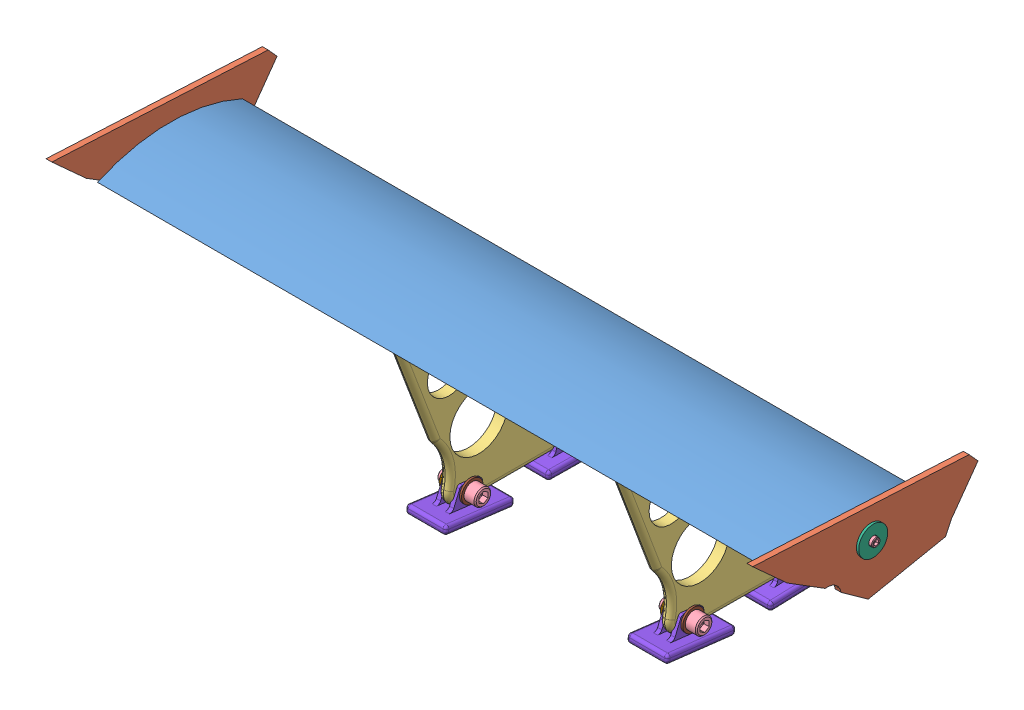
SolidWorks assembly Assem1, configuration Default. Lengths in mm.
Overall size (1241.16 472.25 542.31).
81 component instances, 11 part files, 160 mates.
Components (placement in the parent):
- Part2-1: Part2 [Default] at (342.6125 943.7855 488.4841) size (1200 61 250)
- Part3-1: Part3 [Default] at (1552.6125 952.4935 445.758) x (0 -0.051123 -0.998692) z (-1 0 0) size (390.26 137.82 10)
- Part1-1: Part1 [Default] at (760.6125 644.7182 243.5009) x (0 0.00127 0.999999) z (-1 0 0) size (353.43 346.99 18)
- Part3-2: Part3 [Default] at (342.6125 952.4935 445.758) x (0 -0.051123 -0.998692) z (-1 0 0) size (390.26 137.82 10)
- socket head cap screw_ai-2: socket head cap screw_ai [HX-SHCS 0.375-24x1.625x1.625-N] at (320.9793 952.2239 440.4907) size (50.8 14.29 14.29)
- flat washer type a selected wide_ai-1: flat washer type a selected wide_ai [Selected Wide FW 0.438] at (332.6125 952.2239 440.4907) size (2.11 34.92 34.92)
- socket head cap screw_ai-6: socket head cap screw_ai [HX-SHCS 0.375-24x0.375x0.375-N] at (1562.1375 952.2239 440.4907) x (-1 0 0) z (0 0.924225 0.381849) size (19.05 14.29 14.29)
- flat washer wide_am-1: flat washer wide_am [B18.22M - Plain washer, 14 mm, wide] at (1552.7537 952.2239 440.4907) x (-1 0 0) z (0 -0.924225 -0.381849) size (4 50 50)
- Part4-1: Part4 [Default] at (742.6125 905.2213 468.6071) x (0 0.973052 0.230586) z (-1 0 0) size (44 14 6)
- Part5-1: Part5 [Default] at (750.3125 548.0812 169.7061) x (0 -0.012088 -0.999927) z (0 0.999927 -0.012088) size (120 70 48.08)
- Part4-2: Part4 [Default] at (765.6125 909.909 397.6753) x (0 -0.859139 0.511742) z (-1 0 0) size (44 14 6)
- Part4-3: Part4 [Default] at (765.6125 907.4668 469.1392) x (0 -0.973052 -0.230586) z (-1 0 0) size (44 14 6)
- Part4-4: Part4 [Default] at (742.6125 909.909 397.6753) x (0 -0.859139 0.511742) z (-1 0 0) size (44 14 6)
- Part1-2: Part1 [Default] at (1143.6125 643.7923 244.3096) x (0 0.005793 0.999983) z (-1 0 0) size (353.43 346.99 18)
- Part4-5: Part4 [Default] at (1148.6125 909.8196 397.5231) x (0 -0.865593 0.500748) z (-1 0 0) size (44 14 6)
- Part4-6: Part4 [Default] at (1148.6125 907.5016 468.9956) x (0 -0.970536 -0.240954) z (-1 0 0) size (44 14 6)
- Part4-7: Part4 [Default] at (1125.6125 907.8221 398.6787) x (0 0.865593 -0.500748) z (-1 0 0) size (44 14 6)
- Part4-8: Part4 [Default] at (1125.6125 905.2619 468.4396) x (0 0.970536 0.240954) z (-1 0 0) size (44 14 6)
- socket head cap screw_ai-7: socket head cap screw_ai [HX-SHCS 0.375-24x1.75x1.25-N] at (1107.9793 891.8237 465.1033) size (53.98 14.29 14.29)
- socket head cap screw_ai-8: socket head cap screw_ai [HX-SHCS 0.375-24x1.75x1.25-N] at (1107.9793 920.9398 472.3319) size (53.98 14.29 14.29)
- socket head cap screw_ai-9: socket head cap screw_ai [HX-SHCS 0.375-24x1.75x1.25-N] at (1107.9793 895.837 405.6121) size (53.98 14.29 14.29)
- socket head cap screw_ai-10: socket head cap screw_ai [HX-SHCS 0.375-24x1.75x1.25-N] at (1107.9793 921.8048 390.5896) size (53.98 14.29 14.29)
- socket head cap screw_ai-11: socket head cap screw_ai [HX-SHCS 0.375-24x1.75x1.25-N] at (1107.9793 895.837 405.6121) size (53.98 14.29 14.29)
- socket head cap screw_ai-12: socket head cap screw_ai [HX-SHCS 0.375-24x1.75x1.25-N] at (1107.9793 921.8048 390.5896) size (53.98 14.29 14.29)
- socket head cap screw_ai-13: socket head cap screw_ai [HX-SHCS 0.375-24x1.75x1.25-N] at (1107.9793 891.8237 465.1033) size (53.98 14.29 14.29)
- socket head cap screw_ai-14: socket head cap screw_ai [HX-SHCS 0.375-24x1.75x1.25-N] at (1107.9793 920.9398 472.3319) size (53.98 14.29 14.29)
- socket head cap screw_ai-15: socket head cap screw_ai [HX-SHCS 0.375-24x1.75x1.25-N] at (724.9793 921.8048 390.5896) size (53.98 14.29 14.29)
- socket head cap screw_ai-16: socket head cap screw_ai [HX-SHCS 0.375-24x1.75x1.25-N] at (724.9793 896.0306 405.9419) size (53.98 14.29 14.29)
- socket head cap screw_ai-17: socket head cap screw_ai [HX-SHCS 0.375-24x1.75x1.25-N] at (724.9793 891.7483 465.4143) size (53.98 14.29 14.29)
- socket head cap screw_ai-18: socket head cap screw_ai [HX-SHCS 0.375-24x1.75x1.25-N] at (724.9793 920.9398 472.3319) size (53.98 14.29 14.29)
- socket head cap screw_ai-19: socket head cap screw_ai [HX-SHCS 0.375-24x1.75x1.25-N] at (724.9793 921.8048 390.5896) size (53.98 14.29 14.29)
- socket head cap screw_ai-20: socket head cap screw_ai [HX-SHCS 0.375-24x1.75x1.25-N] at (724.9793 896.0306 405.9419) size (53.98 14.29 14.29)
- socket head cap screw_ai-21: socket head cap screw_ai [HX-SHCS 0.375-24x1.75x1.25-N] at (724.9793 891.7483 465.4143) size (53.98 14.29 14.29)
- socket head cap screw_ai-22: socket head cap screw_ai [HX-SHCS 0.375-24x1.75x1.25-N] at (724.9793 920.9398 472.3319) size (53.98 14.29 14.29)
- hex nut_ai-1: hex nut_ai [HNUT 0.3750-24-D-N] at (774.1723 891.7483 465.4143) x (0 0 -1) z (1 0 0) size (14.27 16.48 8.56)
- hex nut_ai-2: hex nut_ai [HNUT 0.3750-24-D-N] at (774.1723 920.9398 472.3319) x (0 0 -1) z (1 0 0) size (14.27 16.48 8.56)
- hex nut_ai-3: hex nut_ai [HNUT 0.3750-24-D-N] at (774.1723 921.8048 390.5896) x (0 0 -1) z (1 0 0) size (14.27 16.48 8.56)
- hex nut_ai-4: hex nut_ai [HNUT 0.3750-24-D-N] at (774.1723 896.0306 405.9419) x (0 0 -1) z (1 0 0) size (14.27 16.48 8.56)
- hex nut_ai-5: hex nut_ai [HNUT 0.3750-24-D-N] at (774.1723 891.7483 465.4143) x (0 0 -1) z (1 0 0) size (14.27 16.48 8.56)
- hex nut_ai-6: hex nut_ai [HNUT 0.3750-24-D-N] at (774.1723 920.9398 472.3319) x (0 0 -1) z (1 0 0) size (14.27 16.48 8.56)
- hex nut_ai-7: hex nut_ai [HNUT 0.3750-24-D-N] at (774.1723 921.8048 390.5896) x (0 0 -1) z (1 0 0) size (14.27 16.48 8.56)
- hex nut_ai-8: hex nut_ai [HNUT 0.3750-24-D-N] at (774.1723 896.0306 405.9419) x (0 0 -1) z (1 0 0) size (14.27 16.48 8.56)
- hex nut_ai-9: hex nut_ai [HNUT 0.3750-24-D-N] at (1157.1723 891.8237 465.1033) x (0 0 -1) z (1 0 0) size (14.27 16.48 8.56)
- hex nut_ai-10: hex nut_ai [HNUT 0.3750-24-D-N] at (1157.1723 920.9398 472.3319) x (0 0 -1) z (1 0 0) size (14.27 16.48 8.56)
- hex nut_ai-11: hex nut_ai [HNUT 0.3750-24-D-N] at (1157.1723 895.837 405.6121) x (0 0 -1) z (1 0 0) size (14.27 16.48 8.56)
- hex nut_ai-12: hex nut_ai [HNUT 0.3750-24-D-N] at (1157.1723 921.8048 390.5896) x (0 0 -1) z (1 0 0) size (14.27 16.48 8.56)
- hex nut_ai-13: hex nut_ai [HNUT 0.3750-24-D-N] at (1157.1723 895.837 405.6121) x (0 0 -1) z (1 0 0) size (14.27 16.48 8.56)
- hex nut_ai-14: hex nut_ai [HNUT 0.3750-24-D-N] at (1157.1723 921.8048 390.5896) x (0 0 -1) z (1 0 0) size (14.27 16.48 8.56)
- hex nut_ai-15: hex nut_ai [HNUT 0.3750-24-D-N] at (1157.1723 891.8237 465.1033) x (0 0 -1) z (1 0 0) size (14.27 16.48 8.56)
- hex nut_ai-16: hex nut_ai [HNUT 0.3750-24-D-N] at (1157.1723 920.9398 472.3319) x (0 0 -1) z (1 0 0) size (14.27 16.48 8.56)
- flat washer type a selected narrow_ai-1: flat washer type a selected narrow_ai [Selected Narrow FW 0.438] at (736.6125 891.7483 465.4143) size (2.11 22.23 22.23)
- flat washer type a selected narrow_ai-2: flat washer type a selected narrow_ai [Selected Narrow FW 0.438] at (736.6125 920.9398 472.3319) size (2.11 22.23 22.23)
- flat washer type a selected narrow_ai-3: flat washer type a selected narrow_ai [Selected Narrow FW 0.438] at (736.6125 921.8048 390.5896) size (2.11 22.23 22.23)
- flat washer type a selected narrow_ai-4: flat washer type a selected narrow_ai [Selected Narrow FW 0.438] at (736.6125 896.0306 405.9419) size (2.11 22.23 22.23)
- flat washer type a selected narrow_ai-5: flat washer type a selected narrow_ai [Selected Narrow FW 0.438] at (736.6125 891.7483 465.4143) size (2.11 22.23 22.23)
- flat washer type a selected narrow_ai-6: flat washer type a selected narrow_ai [Selected Narrow FW 0.438] at (736.6125 920.9398 472.3319) size (2.11 22.23 22.23)
- flat washer type a selected narrow_ai-7: flat washer type a selected narrow_ai [Selected Narrow FW 0.438] at (736.6125 921.8048 390.5896) size (2.11 22.23 22.23)
- flat washer type a selected narrow_ai-8: flat washer type a selected narrow_ai [Selected Narrow FW 0.438] at (736.6125 896.0306 405.9419) size (2.11 22.23 22.23)
- flat washer type a selected narrow_ai-9: flat washer type a selected narrow_ai [Selected Narrow FW 0.438] at (1119.6125 891.8237 465.1033) size (2.11 22.23 22.23)
- flat washer type a selected narrow_ai-10: flat washer type a selected narrow_ai [Selected Narrow FW 0.438] at (1119.6125 920.9398 472.3319) size (2.11 22.23 22.23)
- flat washer type a selected narrow_ai-11: flat washer type a selected narrow_ai [Selected Narrow FW 0.438] at (1119.6125 895.837 405.6121) size (2.11 22.23 22.23)
- flat washer type a selected narrow_ai-12: flat washer type a selected narrow_ai [Selected Narrow FW 0.438] at (1119.6125 921.8048 390.5896) size (2.11 22.23 22.23)
- flat washer type a selected narrow_ai-13: flat washer type a selected narrow_ai [Selected Narrow FW 0.438] at (1119.6125 895.837 405.6121) size (2.11 22.23 22.23)
- flat washer type a selected narrow_ai-14: flat washer type a selected narrow_ai [Selected Narrow FW 0.438] at (1119.6125 921.8048 390.5896) size (2.11 22.23 22.23)
- flat washer type a selected narrow_ai-15: flat washer type a selected narrow_ai [Selected Narrow FW 0.438] at (1119.6125 891.8237 465.1033) size (2.11 22.23 22.23)
- flat washer type a selected narrow_ai-16: flat washer type a selected narrow_ai [Selected Narrow FW 0.438] at (1119.6125 920.9398 472.3319) size (2.11 22.23 22.23)
- Part5-2: Part5 [Default] at (750.3125 548.8937 348.2234) x (0 -0.123214 -0.99238) z (0 0.99238 -0.123214) size (120 70 48.08)
- Part5-3: Part5 [Default] at (1133.3125 548.4065 349.1194) x (0 -0.1181 -0.993002) z (0 0.993002 -0.1181) size (120 70 48.08)
- Part5-4: Part5 [Default] at (1133.3125 546.8724 169.15) x (0 0.033677 -0.999433) z (0 0.999433 0.033677) size (120 70 48.08)
- socket head cap screw_ai-23: socket head cap screw_ai [HX-SHCS 0.75-16x2x2-N] at (1170.7661 582.682 171.0435) x (-1 0 0) z (0 0 -1) size (69.85 28.57 28.57)
- socket head cap screw_ai-24: socket head cap screw_ai [HX-SHCS 0.75-16x2x2-N] at (1170.7661 584.0897 345.5669) x (-1 0 0) z (0 0 -1) size (69.85 28.57 28.57)
- socket head cap screw_ai-25: socket head cap screw_ai [HX-SHCS 0.75-16x2x2-N] at (787.7661 583.9399 169.9592) x (-1 0 0) z (0 0 -1) size (69.85 28.57 28.57)
- socket head cap screw_ai-26: socket head cap screw_ai [HX-SHCS 0.75-16x2x2-N] at (787.7661 584.5581 344.4871) x (-1 0 0) z (0 0 -1) size (69.85 28.57 28.57)
- flat washer type a narrow_ai-1: flat washer type a narrow_ai [Preferred Narrow FW 0.75] at (765.3125 584.5581 344.4871) x (-1 0 0) z (0 0.924225 0.381849) size (3.4 37.31 37.31)
- flat washer type a narrow_ai-2: flat washer type a narrow_ai [Preferred Narrow FW 0.75] at (765.3125 583.9399 169.9592) x (-1 0 0) z (0 0.924225 0.381849) size (3.4 37.31 37.31)
- flat washer type a narrow_ai-3: flat washer type a narrow_ai [Preferred Narrow FW 0.75] at (1148.3125 584.0897 345.5669) x (-1 0 0) z (0 0.924225 0.381849) size (3.4 37.31 37.31)
- flat washer type a narrow_ai-4: flat washer type a narrow_ai [Preferred Narrow FW 0.75] at (1148.3125 582.682 171.0435) x (-1 0 0) z (0 0.924225 0.381849) size (3.4 37.31 37.31)
- hex nut_ai-24: hex nut_ai [HNUT 0.7500-16-B-N] at (725.7215 584.5581 344.4871) x (0 0 1) z (-1 0 0) size (28.57 33 16.89)
- hex nut_ai-25: hex nut_ai [HNUT 0.7500-16-B-N] at (725.7215 583.9399 169.9592) x (0 0 1) z (-1 0 0) size (28.57 33 16.89)
- hex nut_ai-26: hex nut_ai [HNUT 0.7500-16-B-N] at (1108.7215 584.0897 345.5669) x (0 0 1) z (-1 0 0) size (28.57 33 16.89)
- hex nut_ai-27: hex nut_ai [HNUT 0.7500-16-B-N] at (1108.7215 582.682 171.0435) x (0 0 1) z (-1 0 0) size (28.57 33 16.89)
Mates (geometry in assembly coordinates):
- Coincident1: coincident anti-aligned: plane of Part2-1 through (342.6125 825.7405 450.4698) normal (-1 0 0); plane of Part3-2 through (342.6125 895.0646 515.2182) normal (1 0 0)
- Coincident3: coincident aligned: circle of Part2-1; circle of Part3-2
- Coincident4: coincident anti-aligned: plane of Part2-1 through (1542.6125 825.7405 450.4698) normal (1 0 0); plane of Part3-1 through (1542.6125 895.0646 515.2182) normal (-1 0 0)
- Coincident5: coincident aligned: circle of Part2-1; circle of Part3-1
- Concentric18: concentric aligned: cylinder of socket head cap screw_ai-2 through (289.2293 952.2239 440.4907) axis (-1 0 0) radius 4.7625; cylinder of flat washer type a selected wide_ai-1 through (297.6875 952.2239 440.4907) axis (-1 0 0) radius 5.5626
- Coincident23: coincident anti-aligned: plane of Part3-2 through (332.6125 895.0646 515.2182) normal (-1 0 0); plane of flat washer type a selected wide_ai-1 through (332.6125 957.7865 440.4907) normal (1 0 0)
- Concentric191: concentric aligned: cylinder of Part3-2 through (342.6125 952.2239 440.4907) axis (-1 0 0) radius 5; cylinder of socket head cap screw_ai-2 through (289.2293 952.2239 440.4907) axis (-1 0 0) radius 4.7625
- Coincident241: coincident anti-aligned: plane of socket head cap screw_ai-2 through (330.5043 959.3676 440.4907) normal (1 0 0); plane of flat washer type a selected wide_ai-1 through (330.5043 969.6864 440.4907) normal (-1 0 0)
- Concentric24: concentric anti-aligned: cylinder of Part2-1 through (1512.6125 952.2239 440.4907) axis (1 0 0) radius 5; cylinder of Part3-1 through (1552.6125 952.2239 440.4907) axis (-1 0 0) radius 5
- Concentric26: concentric anti-aligned: cylinder of Part3-1 through (1552.6125 952.2239 440.4907) axis (-1 0 0) radius 5; cylinder of socket head cap screw_ai-6 through (1593.8875 952.2239 440.4907) axis (1 0 0) radius 7.1437
- Coincident30: coincident anti-aligned: plane of Part3-1 through (1552.6125 895.0646 515.2182) normal (1 0 0); plane of socket head cap screw_ai-6 through (1552.6125 949.4961 447.0931) normal (-1 0 0)
- Concentric28: concentric aligned: cylinder of socket head cap screw_ai-6 through (1593.8875 952.2239 440.4907) axis (1 0 0) radius 7.1437; cylinder of flat washer wide_am-1 through (1587.6787 952.2239 440.4907) axis (1 0 0) radius 7.76
- Lock1: lock: unknown of Part2-1; unknown of Part3-2
- Lock2: lock: unknown of Part2-1; unknown of Part3-1
- Coincident245: coincident anti-aligned: circle of Part2-1; circle of Part4-4
- Coincident248: coincident anti-aligned: circle of Part2-1; circle of Part4-1
- Coincident250: coincident aligned: circle of Part1-1; circle of Part4-4
- Coincident251: coincident aligned: circle of Part1-1; circle of Part4-1
- Coincident252: coincident anti-aligned: circle of Part2-1; circle of Part4-2
- Coincident254: coincident aligned: cylinder of Part1-1 through (760.6125 896.0306 405.9419) axis (-1 0 0) radius 5; circle of Part4-2
- Coincident255: coincident anti-aligned: circle of Part2-1; circle of Part4-3
- Concentric192: concentric aligned: cylinder of Part1-1 through (760.6125 891.7483 465.4143) axis (-1 0 0) radius 5; cylinder of Part4-3 through (765.6125 891.7483 465.4143) axis (-1 0 0) radius 5
- Coincident257: coincident anti-aligned: circle of Part2-1; circle of Part4-7
- Coincident258: coincident aligned: circle of Part1-2; circle of Part4-7
- Coincident259: coincident anti-aligned: circle of Part2-1; circle of Part4-8
- Concentric193: concentric aligned: cylinder of Part1-2 through (1143.6125 891.8237 465.1033) axis (-1 0 0) radius 5; cylinder of Part4-8 through (1125.6125 891.8237 465.1033) axis (-1 0 0) radius 5
- Coincident260: coincident anti-aligned: circle of Part2-1; circle of Part4-5
- Coincident262: coincident aligned: circle of Part1-2; cylinder of Part4-5 through (1148.6125 895.837 405.6121) axis (-1 0 0) radius 5
- Coincident263: coincident anti-aligned: circle of Part2-1; circle of Part4-6
- Concentric194: concentric aligned: cylinder of Part1-2 through (1143.6125 891.8237 465.1033) axis (-1 0 0) radius 5; cylinder of Part4-6 through (1148.6125 891.8237 465.1033) axis (-1 0 0) radius 5
- Concentric211: concentric anti-aligned: cylinder of socket head cap screw_ai-21 through (693.2293 891.7483 465.4143) axis (-1 0 0) radius 4.7625; cylinder of hex nut_ai-1 through (749.1348 891.7483 465.4143) axis (1 0 0) radius 4.7625
- Coincident280: coincident anti-aligned: plane of Part4-3 through (765.6125 920.9398 472.3319) normal (1 0 0); plane of hex nut_ai-1 through (765.6125 891.7483 479.6891) normal (-1 0 0)
- Concentric212: concentric anti-aligned: cylinder of socket head cap screw_ai-22 through (693.2293 920.9398 472.3319) axis (-1 0 0) radius 4.7625; cylinder of hex nut_ai-2 through (749.1348 920.9398 472.3319) axis (1 0 0) radius 4.7625
- Coincident281: coincident anti-aligned: plane of Part4-3 through (765.6125 920.9398 472.3319) normal (1 0 0); plane of hex nut_ai-2 through (765.6125 920.9398 486.6067) normal (-1 0 0)
- Concentric213: concentric anti-aligned: cylinder of socket head cap screw_ai-19 through (693.2293 921.8048 390.5896) axis (-1 0 0) radius 4.7625; cylinder of hex nut_ai-3 through (749.1348 921.8048 390.5896) axis (1 0 0) radius 4.7625
- Coincident282: coincident anti-aligned: plane of Part4-2 through (765.6125 921.8048 390.5896) normal (1 0 0); plane of hex nut_ai-3 through (765.6125 921.8048 404.8644) normal (-1 0 0)
- Concentric214: concentric anti-aligned: cylinder of socket head cap screw_ai-20 through (693.2293 896.0306 405.9419) axis (-1 0 0) radius 4.7625; cylinder of hex nut_ai-4 through (749.1348 896.0306 405.9419) axis (1 0 0) radius 4.7625
- Coincident283: coincident anti-aligned: plane of Part4-2 through (765.6125 921.8048 390.5896) normal (1 0 0); plane of hex nut_ai-4 through (765.6125 896.0306 420.2167) normal (-1 0 0)
- Concentric215: concentric anti-aligned: cylinder of socket head cap screw_ai-17 through (693.2293 891.7483 465.4143) axis (-1 0 0) radius 4.7625; cylinder of hex nut_ai-5 through (749.1348 891.7483 465.4143) axis (1 0 0) radius 4.7625
- Coincident284: coincident anti-aligned: plane of Part4-3 through (765.6125 920.9398 472.3319) normal (1 0 0); plane of hex nut_ai-5 through (765.6125 891.7483 479.6891) normal (-1 0 0)
- Concentric216: concentric anti-aligned: cylinder of socket head cap screw_ai-18 through (693.2293 920.9398 472.3319) axis (-1 0 0) radius 4.7625; cylinder of hex nut_ai-6 through (749.1348 920.9398 472.3319) axis (1 0 0) radius 4.7625
- Coincident285: coincident anti-aligned: plane of Part4-3 through (765.6125 920.9398 472.3319) normal (1 0 0); plane of hex nut_ai-6 through (765.6125 920.9398 486.6067) normal (-1 0 0)
- Concentric217: concentric anti-aligned: cylinder of socket head cap screw_ai-15 through (693.2293 921.8048 390.5896) axis (-1 0 0) radius 4.7625; cylinder of hex nut_ai-7 through (749.1348 921.8048 390.5896) axis (1 0 0) radius 4.7625
- Coincident286: coincident anti-aligned: plane of Part4-2 through (765.6125 921.8048 390.5896) normal (1 0 0); plane of hex nut_ai-7 through (765.6125 921.8048 404.8644) normal (-1 0 0)
- Concentric218: concentric anti-aligned: cylinder of socket head cap screw_ai-16 through (693.2293 896.0306 405.9419) axis (-1 0 0) radius 4.7625; cylinder of hex nut_ai-8 through (749.1348 896.0306 405.9419) axis (1 0 0) radius 4.7625
- Coincident287: coincident anti-aligned: plane of Part4-2 through (765.6125 921.8048 390.5896) normal (1 0 0); plane of hex nut_ai-8 through (765.6125 896.0306 420.2167) normal (-1 0 0)
- Concentric219: concentric anti-aligned: cylinder of socket head cap screw_ai-13 through (1076.2293 891.8237 465.1033) axis (-1 0 0) radius 4.7625; cylinder of hex nut_ai-9 through (1132.1348 891.8237 465.1033) axis (1 0 0) radius 4.7625
- Coincident288: coincident anti-aligned: plane of Part4-6 through (1148.6125 920.9398 472.3319) normal (1 0 0); plane of hex nut_ai-9 through (1148.6125 891.8237 479.3781) normal (-1 0 0)
- Concentric220: concentric anti-aligned: cylinder of socket head cap screw_ai-14 through (1076.2293 920.9398 472.3319) axis (-1 0 0) radius 4.7625; cylinder of hex nut_ai-10 through (1132.1348 920.9398 472.3319) axis (1 0 0) radius 4.7625
- Coincident289: coincident anti-aligned: plane of Part4-6 through (1148.6125 920.9398 472.3319) normal (1 0 0); plane of hex nut_ai-10 through (1148.6125 920.9398 486.6067) normal (-1 0 0)
- Concentric221: concentric anti-aligned: cylinder of socket head cap screw_ai-11 through (1076.2293 895.837 405.6121) axis (-1 0 0) radius 4.7625; cylinder of hex nut_ai-11 through (1132.1348 895.837 405.6121) axis (1 0 0) radius 4.7625
- Coincident290: coincident anti-aligned: plane of Part4-5 through (1148.6125 921.8048 390.5896) normal (1 0 0); plane of hex nut_ai-11 through (1148.6125 895.837 419.8869) normal (-1 0 0)
- Concentric222: concentric anti-aligned: cylinder of socket head cap screw_ai-12 through (1076.2293 921.8048 390.5896) axis (-1 0 0) radius 4.7625; cylinder of hex nut_ai-12 through (1132.1348 921.8048 390.5896) axis (1 0 0) radius 4.7625
- Coincident291: coincident anti-aligned: plane of Part4-5 through (1148.6125 921.8048 390.5896) normal (1 0 0); plane of hex nut_ai-12 through (1148.6125 921.8048 404.8644) normal (-1 0 0)
- Concentric223: concentric anti-aligned: cylinder of socket head cap screw_ai-9 through (1076.2293 895.837 405.6121) axis (-1 0 0) radius 4.7625; cylinder of hex nut_ai-13 through (1132.1348 895.837 405.6121) axis (1 0 0) radius 4.7625
- Coincident292: coincident anti-aligned: plane of Part4-5 through (1148.6125 921.8048 390.5896) normal (1 0 0); plane of hex nut_ai-13 through (1148.6125 895.837 419.8869) normal (-1 0 0)
- Concentric224: concentric anti-aligned: cylinder of socket head cap screw_ai-10 through (1076.2293 921.8048 390.5896) axis (-1 0 0) radius 4.7625; cylinder of hex nut_ai-14 through (1132.1348 921.8048 390.5896) axis (1 0 0) radius 4.7625
- Coincident293: coincident anti-aligned: plane of Part4-5 through (1148.6125 921.8048 390.5896) normal (1 0 0); plane of hex nut_ai-14 through (1148.6125 921.8048 404.8644) normal (-1 0 0)
- Concentric225: concentric anti-aligned: cylinder of socket head cap screw_ai-7 through (1076.2293 891.8237 465.1033) axis (-1 0 0) radius 4.7625; cylinder of hex nut_ai-15 through (1132.1348 891.8237 465.1033) axis (1 0 0) radius 4.7625
- Coincident294: coincident anti-aligned: plane of Part4-6 through (1148.6125 920.9398 472.3319) normal (1 0 0); plane of hex nut_ai-15 through (1148.6125 891.8237 479.3781) normal (-1 0 0)
- Concentric226: concentric anti-aligned: cylinder of socket head cap screw_ai-8 through (1076.2293 920.9398 472.3319) axis (-1 0 0) radius 4.7625; cylinder of hex nut_ai-16 through (1132.1348 920.9398 472.3319) axis (1 0 0) radius 4.7625
- Coincident295: coincident anti-aligned: plane of Part4-6 through (1148.6125 920.9398 472.3319) normal (1 0 0); plane of hex nut_ai-16 through (1148.6125 920.9398 486.6067) normal (-1 0 0)
- Concentric227: concentric aligned: cylinder of socket head cap screw_ai-21 through (693.2293 891.7483 465.4143) axis (-1 0 0) radius 4.7625; cylinder of flat washer type a selected narrow_ai-1 through (701.6875 891.7483 465.4143) axis (-1 0 0) radius 5.5626
- Coincident296: coincident anti-aligned: plane of Part4-1 through (736.6125 891.7483 465.4143) normal (-1 0 0); plane of flat washer type a selected narrow_ai-1 through (736.6125 897.3109 465.4143) normal (1 0 0)
- Concentric2281: concentric aligned: cylinder of Part4-1 through (742.6125 891.7483 465.4143) axis (-1 0 0) radius 5; cylinder of socket head cap screw_ai-21 through (693.2293 891.7483 465.4143) axis (-1 0 0) radius 4.7625
- Coincident2971: coincident anti-aligned: plane of socket head cap screw_ai-21 through (734.5043 898.892 465.4143) normal (1 0 0); plane of flat washer type a selected narrow_ai-1 through (734.5043 902.8608 465.4143) normal (-1 0 0)
- Concentric229: concentric aligned: cylinder of socket head cap screw_ai-22 through (693.2293 920.9398 472.3319) axis (-1 0 0) radius 4.7625; cylinder of flat washer type a selected narrow_ai-2 through (701.6875 920.9398 472.3319) axis (-1 0 0) radius 5.5626
- Coincident298: coincident anti-aligned: plane of Part4-1 through (736.6125 891.7483 465.4143) normal (-1 0 0); plane of flat washer type a selected narrow_ai-2 through (736.6125 926.5024 472.3319) normal (1 0 0)
- Concentric2301: concentric aligned: cylinder of Part4-1 through (742.6125 920.9398 472.3319) axis (-1 0 0) radius 5; cylinder of socket head cap screw_ai-22 through (693.2293 920.9398 472.3319) axis (-1 0 0) radius 4.7625
- Coincident2991: coincident anti-aligned: plane of socket head cap screw_ai-22 through (734.5043 928.0836 472.3319) normal (1 0 0); plane of flat washer type a selected narrow_ai-2 through (734.5043 932.0523 472.3319) normal (-1 0 0)
- Concentric231: concentric aligned: cylinder of socket head cap screw_ai-19 through (693.2293 921.8048 390.5896) axis (-1 0 0) radius 4.7625; cylinder of flat washer type a selected narrow_ai-3 through (701.6875 921.8048 390.5896) axis (-1 0 0) radius 5.5626
- Coincident300: coincident anti-aligned: plane of Part4-4 through (736.6125 921.8048 390.5896) normal (-1 0 0); plane of flat washer type a selected narrow_ai-3 through (736.6125 927.3674 390.5896) normal (1 0 0)
- Concentric2321: concentric aligned: cylinder of Part4-4 through (742.6125 921.8048 390.5896) axis (-1 0 0) radius 5; cylinder of socket head cap screw_ai-19 through (693.2293 921.8048 390.5896) axis (-1 0 0) radius 4.7625
- Coincident3011: coincident anti-aligned: plane of socket head cap screw_ai-19 through (734.5043 928.9485 390.5896) normal (1 0 0); plane of flat washer type a selected narrow_ai-3 through (734.5043 932.9173 390.5896) normal (-1 0 0)
- Concentric233: concentric aligned: cylinder of socket head cap screw_ai-20 through (693.2293 896.0306 405.9419) axis (-1 0 0) radius 4.7625; cylinder of flat washer type a selected narrow_ai-4 through (701.6875 896.0306 405.9419) axis (-1 0 0) radius 5.5626
- Coincident302: coincident anti-aligned: plane of Part4-4 through (736.6125 921.8048 390.5896) normal (-1 0 0); plane of flat washer type a selected narrow_ai-4 through (736.6125 901.5932 405.9419) normal (1 0 0)
- Concentric2341: concentric aligned: cylinder of Part4-4 through (742.6125 896.0306 405.9419) axis (-1 0 0) radius 5; cylinder of socket head cap screw_ai-20 through (693.2293 896.0306 405.9419) axis (-1 0 0) radius 4.7625
- Coincident3031: coincident anti-aligned: plane of socket head cap screw_ai-20 through (734.5043 903.1743 405.9419) normal (1 0 0); plane of flat washer type a selected narrow_ai-4 through (734.5043 907.1431 405.9419) normal (-1 0 0)
- Concentric235: concentric aligned: cylinder of socket head cap screw_ai-17 through (693.2293 891.7483 465.4143) axis (-1 0 0) radius 4.7625; cylinder of flat washer type a selected narrow_ai-5 through (701.6875 891.7483 465.4143) axis (-1 0 0) radius 5.5626
- Coincident304: coincident anti-aligned: plane of Part4-1 through (736.6125 891.7483 465.4143) normal (-1 0 0); plane of flat washer type a selected narrow_ai-5 through (736.6125 897.3109 465.4143) normal (1 0 0)
- Concentric2361: concentric aligned: cylinder of Part4-1 through (742.6125 891.7483 465.4143) axis (-1 0 0) radius 5; cylinder of socket head cap screw_ai-17 through (693.2293 891.7483 465.4143) axis (-1 0 0) radius 4.7625
- Coincident3051: coincident anti-aligned: plane of socket head cap screw_ai-17 through (734.5043 898.892 465.4143) normal (1 0 0); plane of flat washer type a selected narrow_ai-5 through (734.5043 902.8608 465.4143) normal (-1 0 0)
- Concentric237: concentric aligned: cylinder of socket head cap screw_ai-18 through (693.2293 920.9398 472.3319) axis (-1 0 0) radius 4.7625; cylinder of flat washer type a selected narrow_ai-6 through (701.6875 920.9398 472.3319) axis (-1 0 0) radius 5.5626
- Coincident306: coincident anti-aligned: plane of Part4-1 through (736.6125 891.7483 465.4143) normal (-1 0 0); plane of flat washer type a selected narrow_ai-6 through (736.6125 926.5024 472.3319) normal (1 0 0)
- Concentric2381: concentric aligned: cylinder of Part4-1 through (742.6125 920.9398 472.3319) axis (-1 0 0) radius 5; cylinder of socket head cap screw_ai-18 through (693.2293 920.9398 472.3319) axis (-1 0 0) radius 4.7625
- Coincident3071: coincident anti-aligned: plane of socket head cap screw_ai-18 through (734.5043 928.0836 472.3319) normal (1 0 0); plane of flat washer type a selected narrow_ai-6 through (734.5043 932.0523 472.3319) normal (-1 0 0)
- Concentric239: concentric aligned: cylinder of socket head cap screw_ai-15 through (693.2293 921.8048 390.5896) axis (-1 0 0) radius 4.7625; cylinder of flat washer type a selected narrow_ai-7 through (701.6875 921.8048 390.5896) axis (-1 0 0) radius 5.5626
- Coincident308: coincident anti-aligned: plane of Part4-4 through (736.6125 921.8048 390.5896) normal (-1 0 0); plane of flat washer type a selected narrow_ai-7 through (736.6125 927.3674 390.5896) normal (1 0 0)
- Concentric2401: concentric aligned: cylinder of Part4-4 through (742.6125 921.8048 390.5896) axis (-1 0 0) radius 5; cylinder of socket head cap screw_ai-15 through (693.2293 921.8048 390.5896) axis (-1 0 0) radius 4.7625
- Coincident3091: coincident anti-aligned: plane of socket head cap screw_ai-15 through (734.5043 928.9485 390.5896) normal (1 0 0); plane of flat washer type a selected narrow_ai-7 through (734.5043 932.9173 390.5896) normal (-1 0 0)
- Concentric241: concentric aligned: cylinder of socket head cap screw_ai-16 through (693.2293 896.0306 405.9419) axis (-1 0 0) radius 4.7625; cylinder of flat washer type a selected narrow_ai-8 through (701.6875 896.0306 405.9419) axis (-1 0 0) radius 5.5626
- Coincident310: coincident anti-aligned: plane of Part4-4 through (736.6125 921.8048 390.5896) normal (-1 0 0); plane of flat washer type a selected narrow_ai-8 through (736.6125 901.5932 405.9419) normal (1 0 0)
- Concentric2421: concentric aligned: cylinder of Part4-4 through (742.6125 896.0306 405.9419) axis (-1 0 0) radius 5; cylinder of socket head cap screw_ai-16 through (693.2293 896.0306 405.9419) axis (-1 0 0) radius 4.7625
- Coincident3111: coincident anti-aligned: plane of socket head cap screw_ai-16 through (734.5043 903.1743 405.9419) normal (1 0 0); plane of flat washer type a selected narrow_ai-8 through (734.5043 907.1431 405.9419) normal (-1 0 0)
- Concentric243: concentric aligned: cylinder of socket head cap screw_ai-13 through (1076.2293 891.8237 465.1033) axis (-1 0 0) radius 4.7625; cylinder of flat washer type a selected narrow_ai-9 through (1084.6875 891.8237 465.1033) axis (-1 0 0) radius 5.5626
- Coincident312: coincident anti-aligned: plane of Part4-8 through (1119.6125 891.8237 465.1033) normal (-1 0 0); plane of flat washer type a selected narrow_ai-9 through (1119.6125 897.3863 465.1033) normal (1 0 0)
- Concentric2441: concentric aligned: cylinder of Part4-8 through (1125.6125 891.8237 465.1033) axis (-1 0 0) radius 5; cylinder of socket head cap screw_ai-13 through (1076.2293 891.8237 465.1033) axis (-1 0 0) radius 4.7625
- Coincident3131: coincident anti-aligned: plane of socket head cap screw_ai-13 through (1117.5043 898.9675 465.1033) normal (1 0 0); plane of flat washer type a selected narrow_ai-9 through (1117.5043 902.9362 465.1033) normal (-1 0 0)
- Concentric245: concentric aligned: cylinder of socket head cap screw_ai-14 through (1076.2293 920.9398 472.3319) axis (-1 0 0) radius 4.7625; cylinder of flat washer type a selected narrow_ai-10 through (1084.6875 920.9398 472.3319) axis (-1 0 0) radius 5.5626
- Coincident314: coincident anti-aligned: plane of Part4-8 through (1119.6125 891.8237 465.1033) normal (-1 0 0); plane of flat washer type a selected narrow_ai-10 through (1119.6125 926.5024 472.3319) normal (1 0 0)
- Concentric2461: concentric aligned: cylinder of Part4-8 through (1125.6125 920.9398 472.3319) axis (-1 0 0) radius 5; cylinder of socket head cap screw_ai-14 through (1076.2293 920.9398 472.3319) axis (-1 0 0) radius 4.7625
- Coincident3151: coincident anti-aligned: plane of socket head cap screw_ai-14 through (1117.5043 928.0836 472.3319) normal (1 0 0); plane of flat washer type a selected narrow_ai-10 through (1117.5043 932.0523 472.3319) normal (-1 0 0)
- Concentric247: concentric aligned: cylinder of socket head cap screw_ai-11 through (1076.2293 895.837 405.6121) axis (-1 0 0) radius 4.7625; cylinder of flat washer type a selected narrow_ai-11 through (1084.6875 895.837 405.6121) axis (-1 0 0) radius 5.5626
- Coincident316: coincident anti-aligned: plane of Part4-7 through (1119.6125 895.837 405.6121) normal (-1 0 0); plane of flat washer type a selected narrow_ai-11 through (1119.6125 901.3996 405.6121) normal (1 0 0)
- Concentric2481: concentric aligned: cylinder of Part4-7 through (1125.6125 895.837 405.6121) axis (-1 0 0) radius 5; cylinder of socket head cap screw_ai-11 through (1076.2293 895.837 405.6121) axis (-1 0 0) radius 4.7625
- Coincident3171: coincident anti-aligned: plane of socket head cap screw_ai-11 through (1117.5043 902.9807 405.6121) normal (1 0 0); plane of flat washer type a selected narrow_ai-11 through (1117.5043 906.9495 405.6121) normal (-1 0 0)
- Concentric249: concentric aligned: cylinder of socket head cap screw_ai-12 through (1076.2293 921.8048 390.5896) axis (-1 0 0) radius 4.7625; cylinder of flat washer type a selected narrow_ai-12 through (1084.6875 921.8048 390.5896) axis (-1 0 0) radius 5.5626
- Coincident318: coincident anti-aligned: plane of Part4-7 through (1119.6125 895.837 405.6121) normal (-1 0 0); plane of flat washer type a selected narrow_ai-12 through (1119.6125 927.3674 390.5896) normal (1 0 0)
- Concentric2501: concentric aligned: cylinder of Part4-7 through (1125.6125 921.8048 390.5896) axis (-1 0 0) radius 5; cylinder of socket head cap screw_ai-12 through (1076.2293 921.8048 390.5896) axis (-1 0 0) radius 4.7625
- Coincident3191: coincident anti-aligned: plane of socket head cap screw_ai-12 through (1117.5043 928.9485 390.5896) normal (1 0 0); plane of flat washer type a selected narrow_ai-12 through (1117.5043 932.9173 390.5896) normal (-1 0 0)
- Concentric251: concentric aligned: cylinder of socket head cap screw_ai-9 through (1076.2293 895.837 405.6121) axis (-1 0 0) radius 4.7625; cylinder of flat washer type a selected narrow_ai-13 through (1084.6875 895.837 405.6121) axis (-1 0 0) radius 5.5626
- Coincident320: coincident anti-aligned: plane of Part4-7 through (1119.6125 895.837 405.6121) normal (-1 0 0); plane of flat washer type a selected narrow_ai-13 through (1119.6125 901.3996 405.6121) normal (1 0 0)
- Concentric2521: concentric aligned: cylinder of Part4-7 through (1125.6125 895.837 405.6121) axis (-1 0 0) radius 5; cylinder of socket head cap screw_ai-9 through (1076.2293 895.837 405.6121) axis (-1 0 0) radius 4.7625
- Coincident3211: coincident anti-aligned: plane of socket head cap screw_ai-9 through (1117.5043 902.9807 405.6121) normal (1 0 0); plane of flat washer type a selected narrow_ai-13 through (1117.5043 906.9495 405.6121) normal (-1 0 0)
- Concentric253: concentric aligned: cylinder of socket head cap screw_ai-10 through (1076.2293 921.8048 390.5896) axis (-1 0 0) radius 4.7625; cylinder of flat washer type a selected narrow_ai-14 through (1084.6875 921.8048 390.5896) axis (-1 0 0) radius 5.5626
- Coincident322: coincident anti-aligned: plane of Part4-7 through (1119.6125 895.837 405.6121) normal (-1 0 0); plane of flat washer type a selected narrow_ai-14 through (1119.6125 927.3674 390.5896) normal (1 0 0)
- Concentric2541: concentric aligned: cylinder of Part4-7 through (1125.6125 921.8048 390.5896) axis (-1 0 0) radius 5; cylinder of socket head cap screw_ai-10 through (1076.2293 921.8048 390.5896) axis (-1 0 0) radius 4.7625
- Coincident3231: coincident anti-aligned: plane of socket head cap screw_ai-10 through (1117.5043 928.9485 390.5896) normal (1 0 0); plane of flat washer type a selected narrow_ai-14 through (1117.5043 932.9173 390.5896) normal (-1 0 0)
- Concentric255: concentric aligned: cylinder of socket head cap screw_ai-7 through (1076.2293 891.8237 465.1033) axis (-1 0 0) radius 4.7625; cylinder of flat washer type a selected narrow_ai-15 through (1084.6875 891.8237 465.1033) axis (-1 0 0) radius 5.5626
- Coincident324: coincident anti-aligned: plane of Part4-8 through (1119.6125 891.8237 465.1033) normal (-1 0 0); plane of flat washer type a selected narrow_ai-15 through (1119.6125 897.3863 465.1033) normal (1 0 0)
- Concentric2561: concentric aligned: cylinder of Part4-8 through (1125.6125 891.8237 465.1033) axis (-1 0 0) radius 5; cylinder of socket head cap screw_ai-7 through (1076.2293 891.8237 465.1033) axis (-1 0 0) radius 4.7625
- Coincident3251: coincident anti-aligned: plane of socket head cap screw_ai-7 through (1117.5043 898.9675 465.1033) normal (1 0 0); plane of flat washer type a selected narrow_ai-15 through (1117.5043 902.9362 465.1033) normal (-1 0 0)
- Concentric257: concentric aligned: cylinder of socket head cap screw_ai-8 through (1076.2293 920.9398 472.3319) axis (-1 0 0) radius 4.7625; cylinder of flat washer type a selected narrow_ai-16 through (1084.6875 920.9398 472.3319) axis (-1 0 0) radius 5.5626
- Coincident326: coincident anti-aligned: plane of Part4-8 through (1119.6125 891.8237 465.1033) normal (-1 0 0); plane of flat washer type a selected narrow_ai-16 through (1119.6125 926.5024 472.3319) normal (1 0 0)
- Concentric2581: concentric aligned: cylinder of Part4-8 through (1125.6125 920.9398 472.3319) axis (-1 0 0) radius 5; cylinder of socket head cap screw_ai-8 through (1076.2293 920.9398 472.3319) axis (-1 0 0) radius 4.7625
- Coincident3271: coincident anti-aligned: plane of socket head cap screw_ai-8 through (1117.5043 928.0836 472.3319) normal (1 0 0); plane of flat washer type a selected narrow_ai-16 through (1117.5043 932.0523 472.3319) normal (-1 0 0)
- Coincident328: coincident aligned: circle of Part1-1; circle of Part5-1
- Concentric267: concentric aligned: circle of Part1-1; circle of Part5-2
- Coincident329: coincident aligned: circle of Part1-2; circle of Part5-4
- Coincident330: coincident anti-aligned: plane of Part1-1 through (742.6125 644.7182 243.5009) normal (-1 0 0); plane of Part5-2 through (742.6125 548.8937 348.2234) normal (1 0 0)
- Concentric270: concentric anti-aligned: cylinder of Part1-1 through (760.6125 584.5581 344.4871) axis (-1 0 0) radius 10.3967; cylinder of Part5-2 through (715.3125 584.5581 344.4871) axis (1 0 0) radius 10
- Lock3: lock: unknown of Part1-1; unknown of Part5-2
- Lock4: lock: unknown of Part1-1; unknown of Part5-1
- Coincident334: coincident anti-aligned: plane of Part1-2 through (1125.6125 643.7923 244.3096) normal (-1 0 0); plane of Part5-3 through (1125.6125 548.4065 349.1194) normal (1 0 0)
- Concentric271: concentric anti-aligned: cylinder of Part1-2 through (1143.6125 584.0897 345.5669) axis (-1 0 0) radius 10.3967; cylinder of Part5-3 through (1098.3125 584.0897 345.5669) axis (1 0 0) radius 10
- Lock5: lock: unknown of Part1-2; unknown of Part5-3
- Concentric283: concentric aligned: cylinder of socket head cap screw_ai-26 through (819.5161 584.5581 344.4871) axis (1 0 0) radius 9.525; cylinder of flat washer type a narrow_ai-1 through (800.2375 584.5581 344.4871) axis (1 0 0) radius 10.3124
- Coincident347: coincident anti-aligned: plane of Part5-2 through (765.3125 548.8937 348.2234) normal (1 0 0); plane of flat washer type a narrow_ai-1 through (765.3125 580.6204 354.018) normal (-1 0 0)
- Concentric2841: concentric aligned: cylinder of Part5-2 through (715.3125 584.5581 344.4871) axis (1 0 0) radius 10; cylinder of socket head cap screw_ai-26 through (819.5161 584.5581 344.4871) axis (1 0 0) radius 9.525
- Coincident3481: coincident anti-aligned: plane of socket head cap screw_ai-26 through (768.7161 598.8456 344.4871) normal (-1 0 0); plane of flat washer type a narrow_ai-1 through (768.7161 577.4342 361.7297) normal (1 0 0)
- Concentric285: concentric aligned: cylinder of socket head cap screw_ai-25 through (819.5161 583.9399 169.9592) axis (1 0 0) radius 9.525; cylinder of flat washer type a narrow_ai-2 through (800.2375 583.9399 169.9592) axis (1 0 0) radius 10.3124
- Coincident349: coincident anti-aligned: plane of Part5-1 through (765.3125 548.0812 169.7061) normal (1 0 0); plane of flat washer type a narrow_ai-2 through (765.3125 580.0021 179.4901) normal (-1 0 0)
- Concentric2861: concentric aligned: cylinder of Part5-1 through (715.3125 583.9399 169.9592) axis (1 0 0) radius 10; cylinder of socket head cap screw_ai-25 through (819.5161 583.9399 169.9592) axis (1 0 0) radius 9.525
- Coincident3501: coincident anti-aligned: plane of socket head cap screw_ai-25 through (768.7161 598.2274 169.9592) normal (-1 0 0); plane of flat washer type a narrow_ai-2 through (768.7161 576.816 187.2018) normal (1 0 0)
- Concentric287: concentric aligned: cylinder of socket head cap screw_ai-24 through (1202.5161 584.0897 345.5669) axis (1 0 0) radius 9.525; cylinder of flat washer type a narrow_ai-3 through (1183.2375 584.0897 345.5669) axis (1 0 0) radius 10.3124
- Coincident351: coincident anti-aligned: plane of Part5-3 through (1148.3125 548.4065 349.1194) normal (1 0 0); plane of flat washer type a narrow_ai-3 through (1148.3125 580.1519 355.0978) normal (-1 0 0)
- Concentric2881: concentric aligned: cylinder of Part5-3 through (1098.3125 584.0897 345.5669) axis (1 0 0) radius 10; cylinder of socket head cap screw_ai-24 through (1202.5161 584.0897 345.5669) axis (1 0 0) radius 9.525
- Coincident3521: coincident anti-aligned: plane of socket head cap screw_ai-24 through (1151.7161 598.3772 345.5669) normal (-1 0 0); plane of flat washer type a narrow_ai-3 through (1151.7161 576.9658 362.8095) normal (1 0 0)
- Concentric289: concentric aligned: cylinder of socket head cap screw_ai-23 through (1202.5161 582.682 171.0435) axis (1 0 0) radius 9.525; cylinder of flat washer type a narrow_ai-4 through (1183.2375 582.682 171.0435) axis (1 0 0) radius 10.3124
- Coincident353: coincident anti-aligned: plane of Part5-4 through (1148.3125 546.8724 169.15) normal (1 0 0); plane of flat washer type a narrow_ai-4 through (1148.3125 578.7442 180.5745) normal (-1 0 0)
- Concentric2901: concentric aligned: cylinder of Part5-4 through (1098.3125 582.682 171.0435) axis (1 0 0) radius 10; cylinder of socket head cap screw_ai-23 through (1202.5161 582.682 171.0435) axis (1 0 0) radius 9.525
- Coincident3541: coincident anti-aligned: plane of socket head cap screw_ai-23 through (1151.7161 596.9695 171.0435) normal (-1 0 0); plane of flat washer type a narrow_ai-4 through (1151.7161 575.5581 188.2862) normal (1 0 0)
- Concentric291: concentric anti-aligned: cylinder of socket head cap screw_ai-26 through (819.5161 584.5581 344.4871) axis (1 0 0) radius 9.525; cylinder of hex nut_ai-24 through (750.7591 584.5581 344.4871) axis (-1 0 0) radius 9.525
- Coincident355: coincident anti-aligned: plane of Part1-1 through (742.6125 644.7182 243.5009) normal (-1 0 0); plane of hex nut_ai-24 through (742.6125 601.0559 344.4871) normal (1 0 0)
- Concentric292: concentric anti-aligned: cylinder of socket head cap screw_ai-25 through (819.5161 583.9399 169.9592) axis (1 0 0) radius 9.525; cylinder of hex nut_ai-25 through (750.7591 583.9399 169.9592) axis (-1 0 0) radius 9.525
- Coincident356: coincident anti-aligned: plane of Part1-1 through (742.6125 644.7182 243.5009) normal (-1 0 0); plane of hex nut_ai-25 through (742.6125 600.4377 169.9592) normal (1 0 0)
- Concentric293: concentric anti-aligned: cylinder of socket head cap screw_ai-24 through (1202.5161 584.0897 345.5669) axis (1 0 0) radius 9.525; cylinder of hex nut_ai-26 through (1133.7591 584.0897 345.5669) axis (-1 0 0) radius 9.525
- Coincident357: coincident anti-aligned: plane of Part1-2 through (1125.6125 643.7923 244.3096) normal (-1 0 0); plane of hex nut_ai-26 through (1125.6125 600.5875 345.5669) normal (1 0 0)
- Concentric294: concentric anti-aligned: cylinder of socket head cap screw_ai-23 through (1202.5161 582.682 171.0435) axis (1 0 0) radius 9.525; cylinder of hex nut_ai-27 through (1133.7591 582.682 171.0435) axis (-1 0 0) radius 9.525
- Coincident358: coincident anti-aligned: plane of Part1-2 through (1125.6125 643.7923 244.3096) normal (-1 0 0); plane of hex nut_ai-27 through (1125.6125 599.1798 171.0435) normal (1 0 0)
